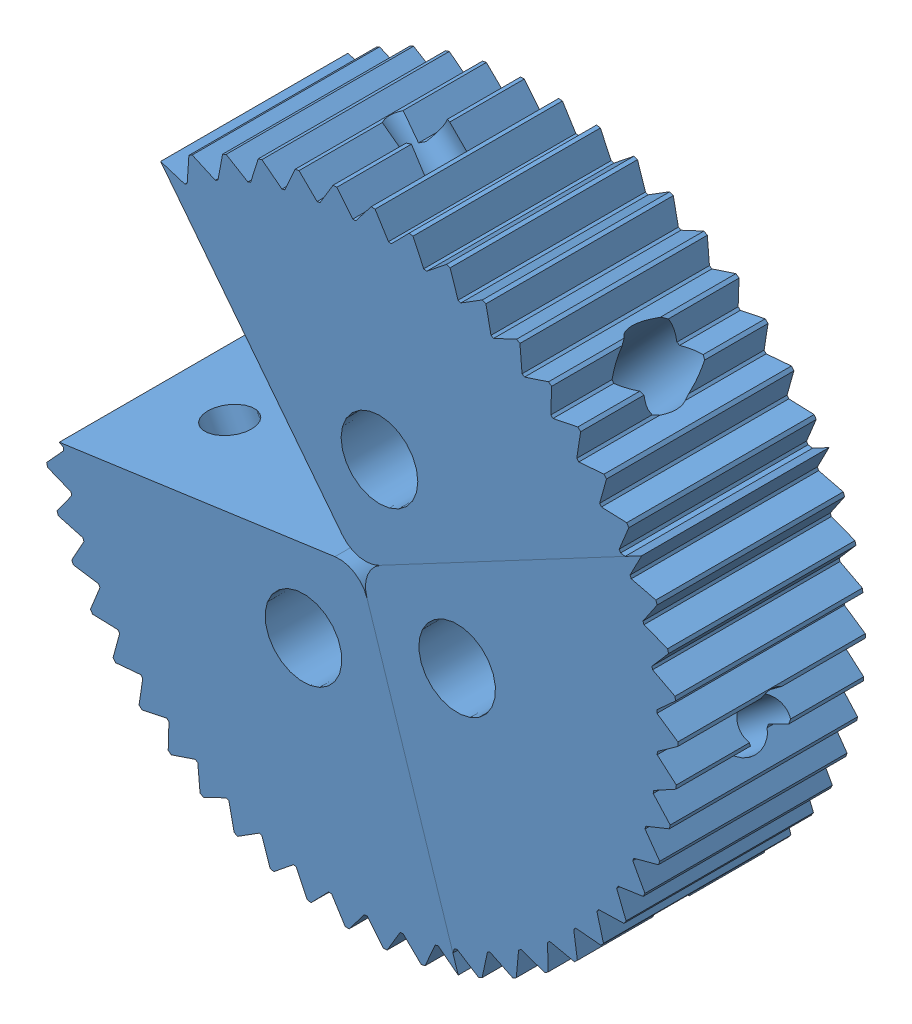
SolidWorks assembly wedge v-6 15-Nov-2017_5mm 270deg, configuration Default. Lengths in mm.
Overall size (51.77 47.26 6.35).
3 component instances, 1 part files, 4 mates.
Components (placement in the parent):
- wedge v-5 14-Sep-2017_5mm-1: wedge v-5 14-Sep-2017_5mm [Default] at (8.9872 12.1194 25.4222) size (31.24 27.17 6.35)
- wedge v-5 14-Sep-2017_5mm-2: wedge v-5 14-Sep-2017_5mm [Default] at (0.0575 0.8989 25.4222) x (-0.173648 -0.984808 0) z (0 0 1) size (31.24 27.17 6.35)
- wedge v-5 14-Sep-2017_5mm-3: wedge v-5 14-Sep-2017_5mm [Default] at (-9.4567 11.6869 25.4222) x (-0.939693 0.34202 0) z (0 0 1) size (31.24 27.17 6.35)
Mates (geometry in assembly coordinates):
- Coincident2: coincident anti-aligned: plane of wedge v-5 14-Sep-2017_5mm-1 through (0.5124 10.6587 22.2472) normal (0.469393 -0.88299 0); plane of wedge v-5 14-Sep-2017_5mm-2 through (9.4022 15.3844 22.2472) normal (-0.469393 0.88299 0)
- Coincident3: coincident anti-aligned: line of wedge v-5 14-Sep-2017_5mm-1 through (0.5124 10.6587 28.5972) axis (0.88299 0.469393 0); line of wedge v-5 14-Sep-2017_5mm-2 through (9.4022 15.3844 28.5972) axis (-0.88299 -0.469393 0)
- Coincident5: coincident anti-aligned: plane of wedge v-5 14-Sep-2017_5mm-2 through (0.0906 9.4986 22.2472) normal (-0.951084 -0.308932 0); plane of wedge v-5 14-Sep-2017_5mm-3 through (3.1861 -0.0312 22.2472) normal (0.951084 0.308932 0)
- Coincident6: coincident anti-aligned: line of wedge v-5 14-Sep-2017_5mm-2 through (0.0906 9.4986 28.5972) axis (0.308932 -0.951084 0); line of wedge v-5 14-Sep-2017_5mm-3 through (3.1861 -0.0312 28.5972) axis (-0.308932 0.951084 0)
